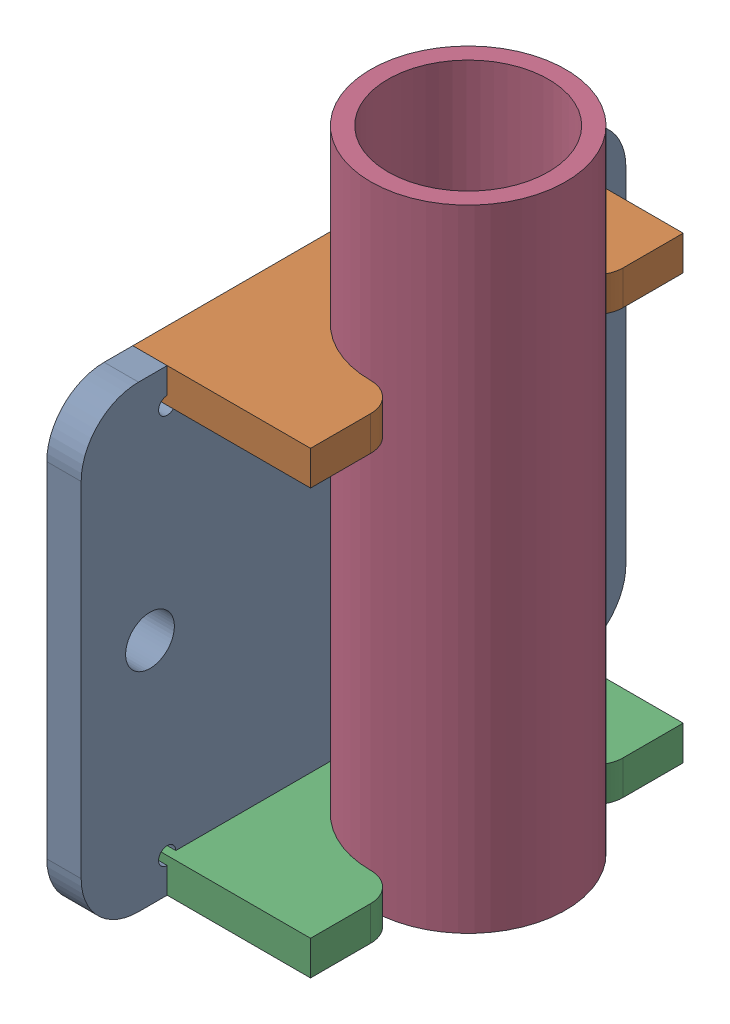
SolidWorks assembly Slider bracket, configuration Default. Lengths in mm.
Overall size (43 110 95).
3 component instances, 3 part files, 0 mates.
Components (placement in the parent):
- Guide plate coldpress-1: Guide plate coldpress [Default] at (671 -169.5566 -2.5) x (0 0 1) z (-1 0 0) size (95 80 6)
- Guide bracket-1: Guide bracket [Default] at (665 -169.5566 -697.5) x (0 0 -1) z (1 0 0) size (65 80 31)
- Slider tube-1: Slider tube [Default] at (665 -149.5566 -697.5) x (0 0 1) z (0 -1 0) size (34 34 110)
